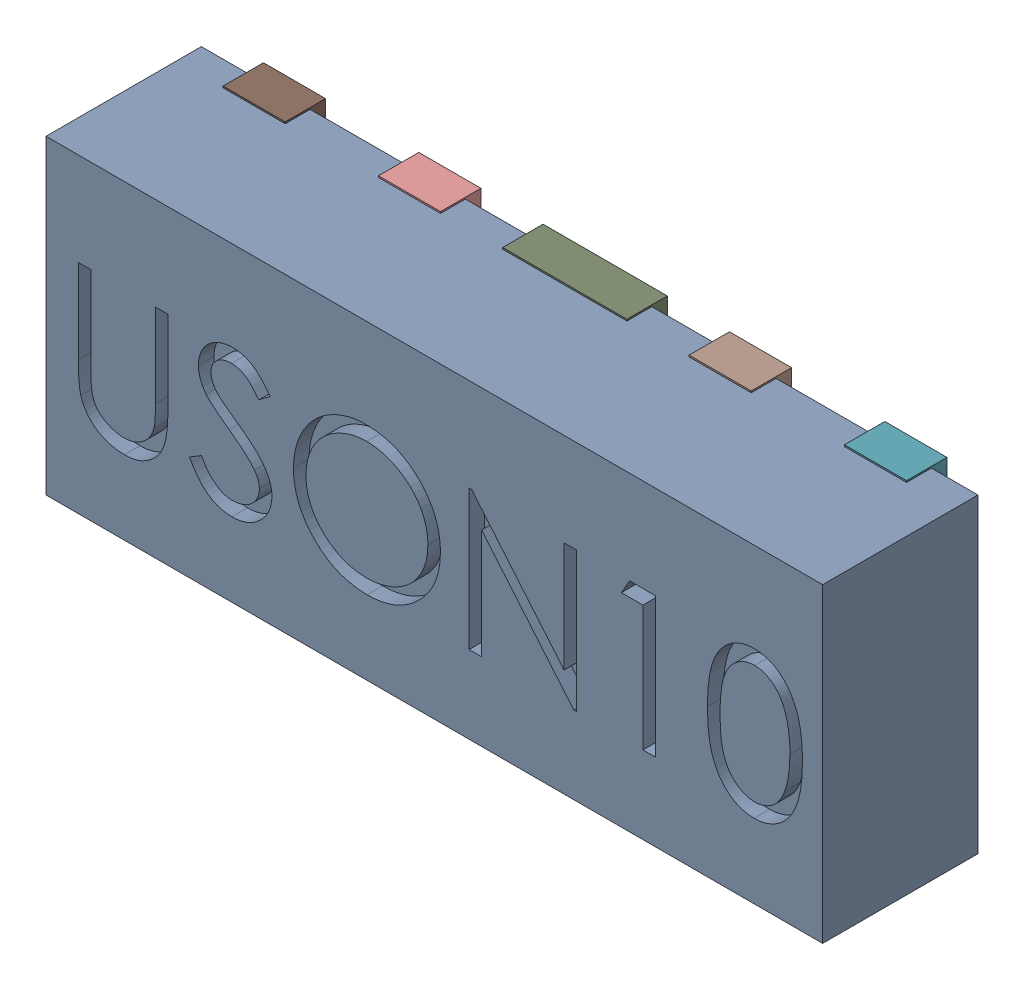
SolidWorks assembly D36, configuration Défaut. Lengths in mm.
Overall size (2.5 1.01 0.55).
12 component instances, 5 part files, 0 mates.
Components (placement in the parent):
- UDFN10-1: UDFN10 [Défaut] at (47.9807 -33.5737 -0.9099) x (1 0 0) z (0 -1 0) size (2.5 0.55 1.01)
  - User Library-UDFN10_Body-1: User Library-UDFN10_Body [Défaut] at (1.0785 0.9721 1.8983) size (2.5 0.5 1)
  - User Library-UDFN10_Pin1-1: User Library-UDFN10_Pin1 [Défaut] at (0.0785 1.0521 2.2208) x (0 0 -1) z (-1 0 0) size (0.37 0.13 0.2)
  - User Library-UDFN10_Pin2-1: User Library-UDFN10_Pin2 [Défaut] at (0.5785 1.0521 2.2208) x (0 0 1) z (1 0 0) size (0.37 0.13 0.2)
  - User Library-UDFN10_Pin4-1: User Library-UDFN10_Pin4 [Défaut] at (1.0785 0.9221 2.2208) x (0 0 1) z (-1 0 0) size (0.49 0.13 0.4)
  - User Library-UDFN10_Pin2-2: User Library-UDFN10_Pin2 [Défaut] at (1.5785 0.9221 2.2208) x (0 0 1) z (-1 0 0) size (0.37 0.13 0.2)
  - User Library-UDFN10_Pin2-3: User Library-UDFN10_Pin2 [Défaut] at (2.0785 0.9221 2.2208) x (0 0 1) z (-1 0 0) size (0.37 0.13 0.2)
  - User Library-UDFN10_Pin2-4: User Library-UDFN10_Pin2 [Défaut] at (2.0785 0.9221 1.5758) x (0 0 -1) z (1 0 0) size (0.37 0.13 0.2)
  - User Library-UDFN10_Pin2-5: User Library-UDFN10_Pin2 [Défaut] at (1.5785 0.9221 1.5758) x (0 0 -1) z (1 0 0) size (0.37 0.13 0.2)
  - User Library-UDFN10_Pin3-1: User Library-UDFN10_Pin3 [Défaut] at (1.0785 0.9221 1.5758) x (0 0 1) z (-1 0 0) size (0.37 0.13 0.4)
  - User Library-UDFN10_Pin2-6: User Library-UDFN10_Pin2 [Défaut] at (0.5785 0.9221 1.5758) x (0 0 -1) z (1 0 0) size (0.37 0.13 0.2)
  - User Library-UDFN10_Pin2-7: User Library-UDFN10_Pin2 [Défaut] at (0.0785 0.9221 1.5758) x (0 0 -1) z (1 0 0) size (0.37 0.13 0.2)
